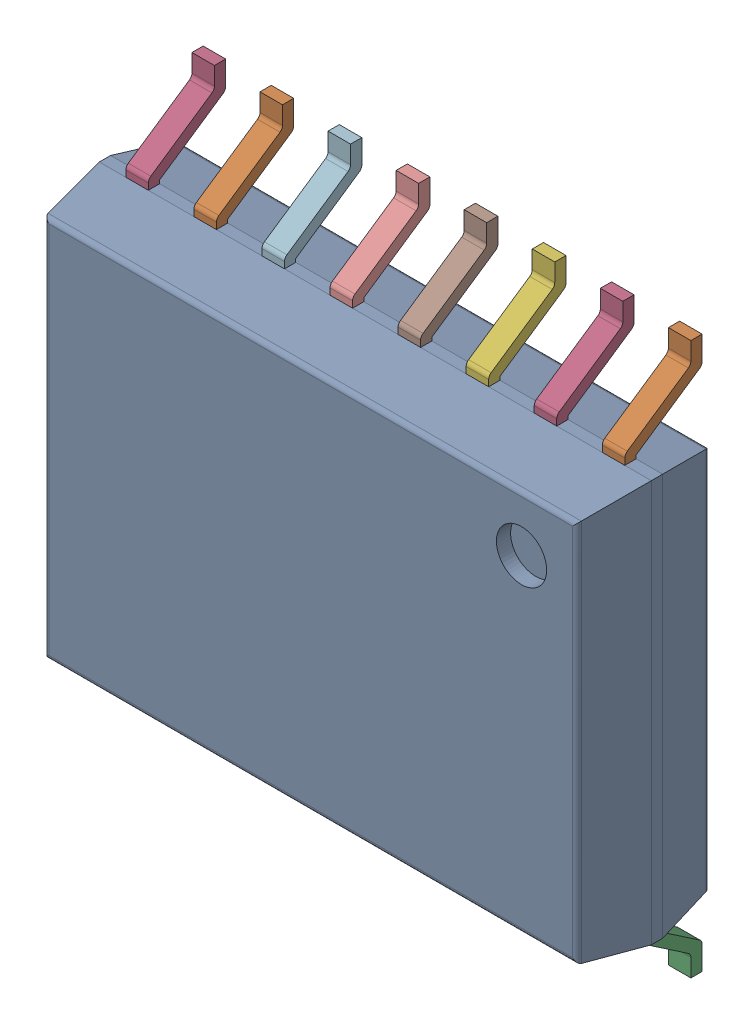
SolidWorks assembly IC3_1.step, configuration Default. Lengths in mm.
Overall size (10.3 10.3 2.65).
3 component instances, 2 part files, 0 mates.
Components (placement in the parent):
- 6383678080.step-1: 6383678080.step [Default] at (79.756 101.397 0) x (0 -1 0) z (0 0 1) size (10.3 10.3 2.65)
  - Body-0_3.step-14: Body-0_3.step [Default] at origin size (7.5 10.3 2.48)
  - PinsArrayLR_4.step-14: PinsArrayLR_4.step [Default] at origin size (10.3 9.31 1.44)
